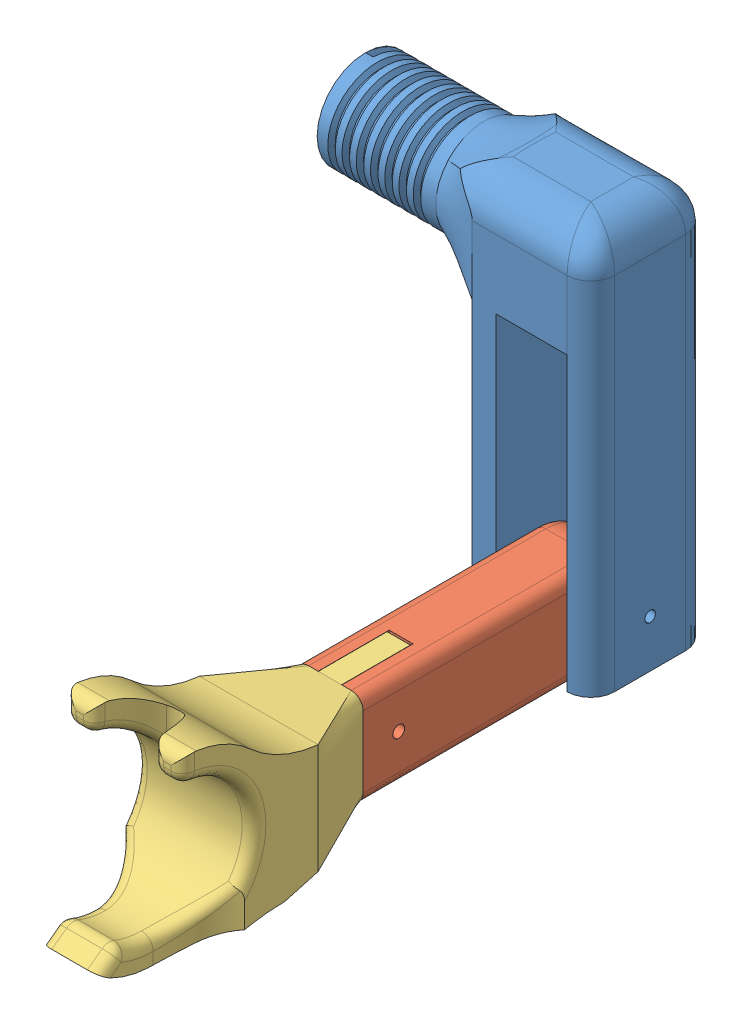
SolidWorks assembly Montagem3, configuration Valor predeterminado. Lengths in mm.
Overall size (121.5 183.78 245.15).
3 component instances, 3 part files, 6 mates.
Components (placement in the parent):
- Braço invertido-1: Braço invertido [Valor predeterminado] at (-149.9995 -84.2407 143.7505) x (0 1 0) z (0 0 1) size (168.75 120 50.02)
- antebraço 2-1: antebraço 2 [Valor predeterminado] at (21.0005 -44.2407 158.7505) x (0 0 1) z (1 0 0) size (120 40 28)
- mão versao 2-1: mão versao 2 [Valor predeterminado] at (60.0005 -76.3136 268.7505) x (-1 0 0) z (0 0 -1) size (52.99 82 139.15)
Mates (geometry in assembly coordinates):
- Concêntrico3: concentric anti-aligned: cylinder of Braço invertido-1 through (10.0005 -64.2407 168.7505) axis (1 0 0) radius 2.25; cylinder of antebraço 2-1 through (49.0005 -64.2407 168.7505) axis (-1 0 0) radius 2.25
- Distância3: distance = 1 mm anti-aligned: plane of antebraço 2-1 through (21.0005 -44.2407 158.7505) normal (-1 0 0); plane of Braço invertido-1 through (20.0005 -84.2407 193.7505) normal (1 0 0)
- Paralelo2: parallel anti-aligned: plane of antebraço 2-1 through (49.0005 -84.2407 158.7505) normal (0 -1 0)
- Paralelo3: parallel: plane of antebraço 2-1 through (21.0005 -44.2407 248.7505) normal (0 0 1); plane of mão versao 2-1 through (60.0005 -76.3136 249.7505) normal (0 0 -1)
- Coincidente12: coincident: point of assembly; point of assembly; moEndPointRef_w of antebraço 2-1; moEndPointRef_w of mão versao 2-1
- Coincidente13: coincident: unknown of antebraço 2-1; unknown of mão versao 2-1
